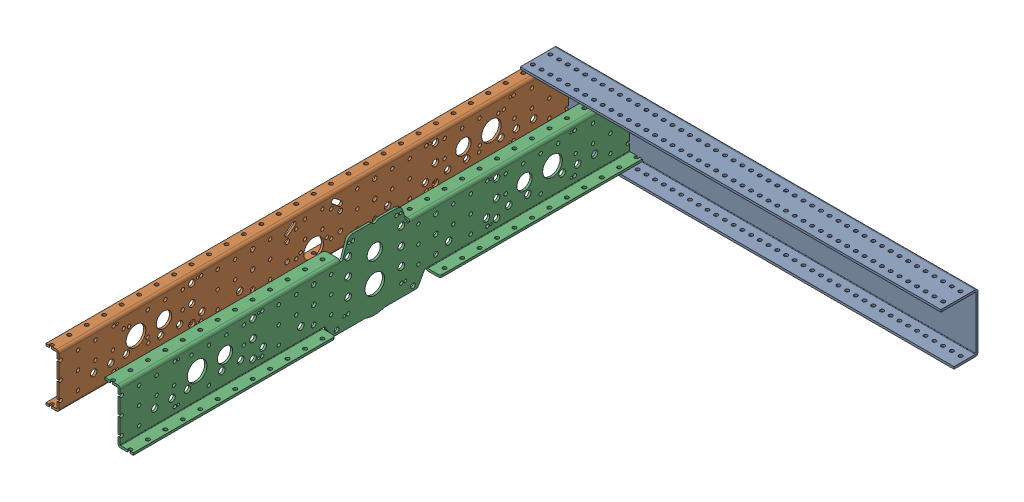
SolidWorks assembly AM14U6 Long Frame Half, configuration Default. Lengths in mm.
Overall size (612 118.39 744.06).
3 component instances, 3 part files, 6 mates.
Components (placement in the parent):
- am-3920 AM14U6 End Plate Long Centered Cut-1: am-3920 AM14U6 End Plate Long Centered Cut [Default] at (-867.1945 -81.407 -3.175) x (1 0 0) z (0 -1 0) size (612 53.98 84.58)
- am-3921b AM14U5 On Grid Outside Plate_Long Configuration-1: am-3921b AM14U5 On Grid Outside Plate_Long Configuration [Default] at (-838.6195 -77.216 776.84) x (0 0 -1) z (0 -1 0) size (740.88 19.05 77.72)
- am-3922b AM14U6 Inside Plate_Long Configuration-1: am-3922b AM14U6 Inside Plate_Long Configuration [Default] at (-749.7195 -77.216 776.84) x (0 0 -1) z (0 -1 0) size (740.88 41.28 118.39)
Mates (geometry in assembly coordinates):
- Width1: width anti-aligned: plane of am-3920 AM14U6 End Plate Long Centered Cut-1 through (-867.1945 -81.407 31.75) normal (0 1 0); plane of am-3920 AM14U6 End Plate Long Centered Cut-1 through (-79.7945 -3.175 50.8) normal (0 -1 0); plane of am-3921b AM14U5 On Grid Outside Plate_Long Configuration-1 through (-838.6195 -81.153 -35.96) normal (0 -1 0); plane of am-3921b AM14U5 On Grid Outside Plate_Long Configuration-1 through (-838.6195 -3.429 -35.96) normal (0 1 0)
- Width2: width: plane of am-3920 AM14U6 End Plate Long Centered Cut-1 through (-867.1945 -84.582 31.75) normal (0 -1 0); plane of am-3920 AM14U6 End Plate Long Centered Cut-1 through (-79.7945 0 50.8) normal (0 1 0); plane of am-3922b AM14U6 Inside Plate_Long Configuration-1 through (-746.5445 -81.153 -24.638) normal (0 -1 0); plane of am-3922b AM14U6 Inside Plate_Long Configuration-1 through (-749.7195 -3.429 -24.638) normal (0 1 0)
- Coincident5: coincident anti-aligned: plane of am-3920 AM14U6 End Plate Long Centered Cut-1 through (-867.1945 -3.175 0) normal (0 0 1); plane of am-3921b AM14U5 On Grid Outside Plate_Long Configuration-1 through (-854.4945 33.023 0) normal (0 0 -1)
- Coincident6: coincident aligned: plane of am-3920 AM14U6 End Plate Long Centered Cut-1 through (-854.4945 -84.582 50.8) normal (-1 0 0); plane of am-3921b AM14U5 On Grid Outside Plate_Long Configuration-1 through (-854.4945 -77.216 776.84) normal (-1 0 0)
- Distance1: distance = 88.9 mm: plane of am-3921b AM14U5 On Grid Outside Plate_Long Configuration-1 through (-835.4445 -7.366 776.84) normal (1 0 0); plane of am-3922b AM14U6 Inside Plate_Long Configuration-1 through (-746.5445 -7.366 776.84) normal (1 0 0)
- Coincident7: coincident anti-aligned: plane of am-3920 AM14U6 End Plate Long Centered Cut-1 through (-867.1945 -3.175 0) normal (0 0 1); plane of am-3922b AM14U6 Inside Plate_Long Configuration-1 through (-727.4945 -119.2313 0) normal (0 0 -1)
